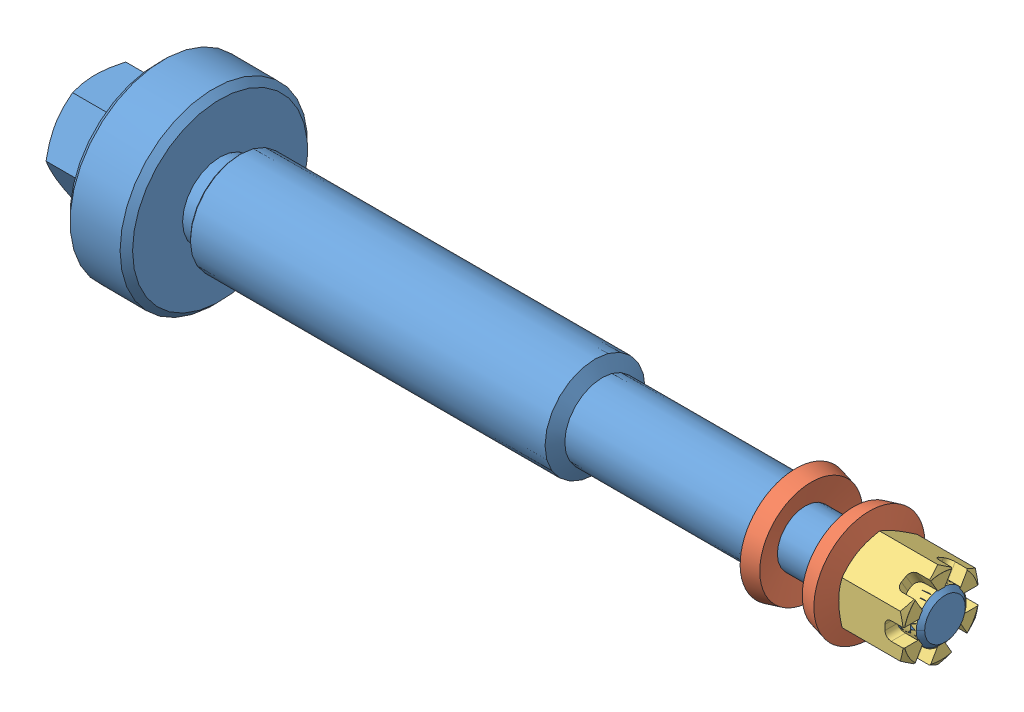
SolidWorks assembly g1_3_1_1_7_1, configuration 默认. Lengths in mm.
Overall size (272.02 60 60).
4 component instances, 3 part files, 0 mates.
Components (placement in the parent):
- g1_3_1_1_7-1_1-1: g1_3_1_1_7-1_1 [默认] at origin size (272.02 60 60)
- a35_5_gb1972_1-1: a35_5_gb1972_1 [默认] at (39.2167 0 0) x (0 0.075145 0.997173) z (0 0.997173 -0.075145) size (35.5 7.2 35.5)
- a35_5_gb1972_1-2: a35_5_gb1972_1 [默认] at (62.8167 0 0) x (0 -0.99777 0.066751) z (0 -0.066751 -0.99777) size (35.5 7.2 35.5)
- m16a_gb6178_1-1: m16a_gb6178_1 [默认] at (85.8167 13.8564 0) x (0 -1 0) z (-1 0 0) size (27.71 24 20.8)
